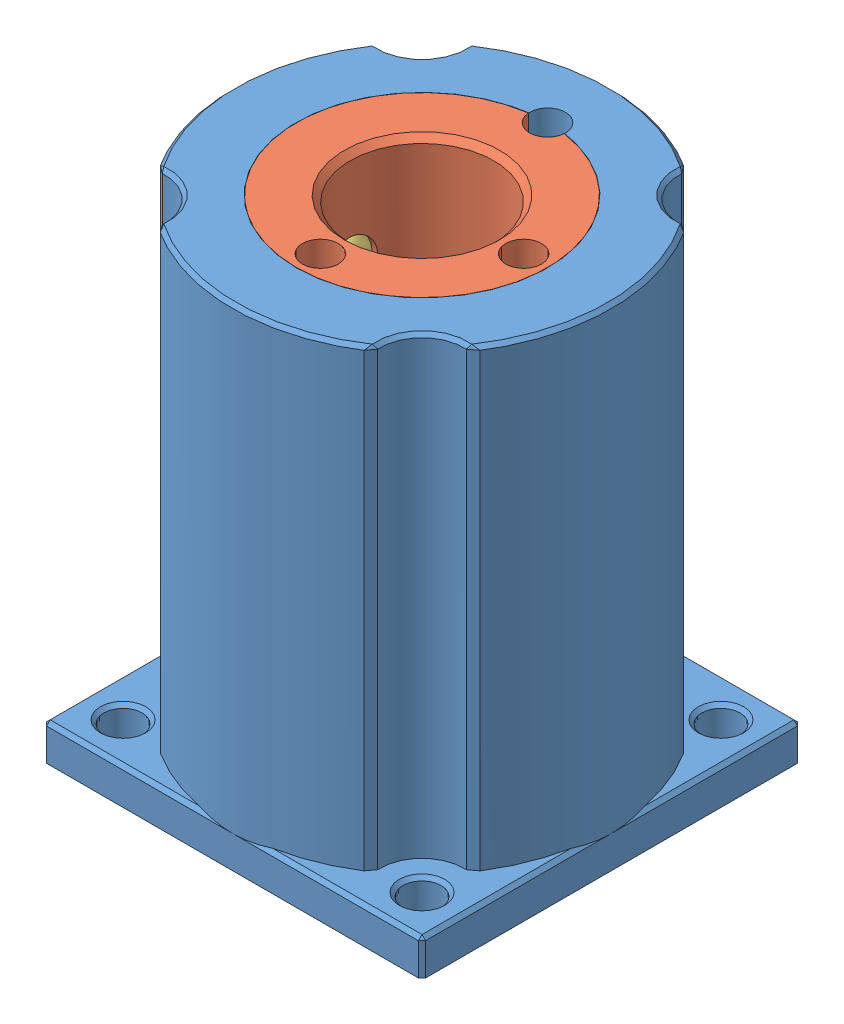
SolidWorks assembly Brillouin laser incoupler, configuration Default. Lengths in mm.
Overall size (31.7 41 31.7).
6 component instances, 4 part files, 11 mates.
Components (placement in the parent):
- in coupler-1: in coupler [Default] at (9.3737 -6.068 38.3523) size (31.7 41 31.7)
- in coupler insert-1: in coupler insert [Default] at (9.3737 -3.068 38.3523) size (21 38 21)
- 3-16in steel ball-1: 3-16in steel ball [Default] at (1.8375 3.932 38.3523) x (0.568361 0.821082 -0.052813) z (-0.819572 0.559316 -0.124369) size (4.76 4.76 4.76)
- 3-16in steel ball-2: 3-16in steel ball [Default] at (1.8375 26.932 38.3523) x (-0.957727 -0.083912 0.275168) z (0.285332 -0.15517 0.945784) size (4.76 4.76 4.76)
- M6x1.0x4 set screw mock up-1: M6x1.0x4 set screw mock up [Default] at (-2.4763 26.932 38.3523) x (0 0.935585 -0.353101) z (0 0.353101 0.935585) size (6 4 6)
- M6x1.0x4 set screw mock up-2: M6x1.0x4 set screw mock up [Default] at (-6.4763 3.932 38.3523) x (0 0.572959 -0.819584) z (0 -0.819584 -0.572959) size (6 4 6)
Mates (geometry in assembly coordinates):
- Concentric1: concentric anti-aligned: cylinder of in coupler-1 through (9.3737 -32.8372 38.3523) axis (0 1 0) radius 10.525; cylinder of in coupler insert-1 through (9.3737 34.932 38.3523) axis (0 -1 0) radius 10.5
- Coincident1: coincident anti-aligned: plane of in coupler-1 through (9.3737 -3.068 38.3523) normal (0 1 0); plane of in coupler insert-1 through (9.3737 -3.068 38.3523) normal (0 -1 0)
- Coincident2: coincident aligned: plane of in coupler-1 through (9.3737 -6.068 38.3523) normal (0 0 1); plane of in coupler insert-1 through (9.3737 -3.068 38.3523) normal (0 0 1)
- Concentric2: concentric: cylinder of in coupler insert-1 through (-1.1263 26.932 38.3523) axis (-1 0 0) radius 2.5; sphere of 3-16in steel ball-2
- Coincident4: coincident: circle of in coupler insert-1; sphere of 3-16in steel ball-2
- Concentric3: concentric: cylinder of in coupler insert-1 through (-1.1263 3.932 38.3523) axis (-1 0 0) radius 2.5; sphere of 3-16in steel ball-1
- Coincident5: coincident: circle of in coupler insert-1; sphere of 3-16in steel ball-1
- Concentric6: concentric aligned: cylinder of in coupler-1 through (-6.4763 3.932 38.3523) axis (-1 0 0) radius 2.5; cylinder of M6x1.0x4 set screw mock up-2 through (-2.4763 3.932 38.3523) axis (-1 0 0) radius 3
- Concentric7: concentric anti-aligned: cylinder of in coupler-1 through (-6.4763 26.932 38.3523) axis (-1 0 0) radius 2.5; cylinder of M6x1.0x4 set screw mock up-1 through (-6.4763 26.932 38.3523) axis (1 0 0) radius 3
- Coincident6: coincident aligned: plane of in coupler-1 through (-6.4763 -3.068 54.2023) normal (-1 0 0); plane of M6x1.0x4 set screw mock up-1 through (-6.4763 26.932 38.3523) normal (-1 0 0)
- Coincident7: coincident anti-aligned: plane of in coupler-1 through (-6.4763 -3.068 54.2023) normal (-1 0 0); circle of M6x1.0x4 set screw mock up-2
